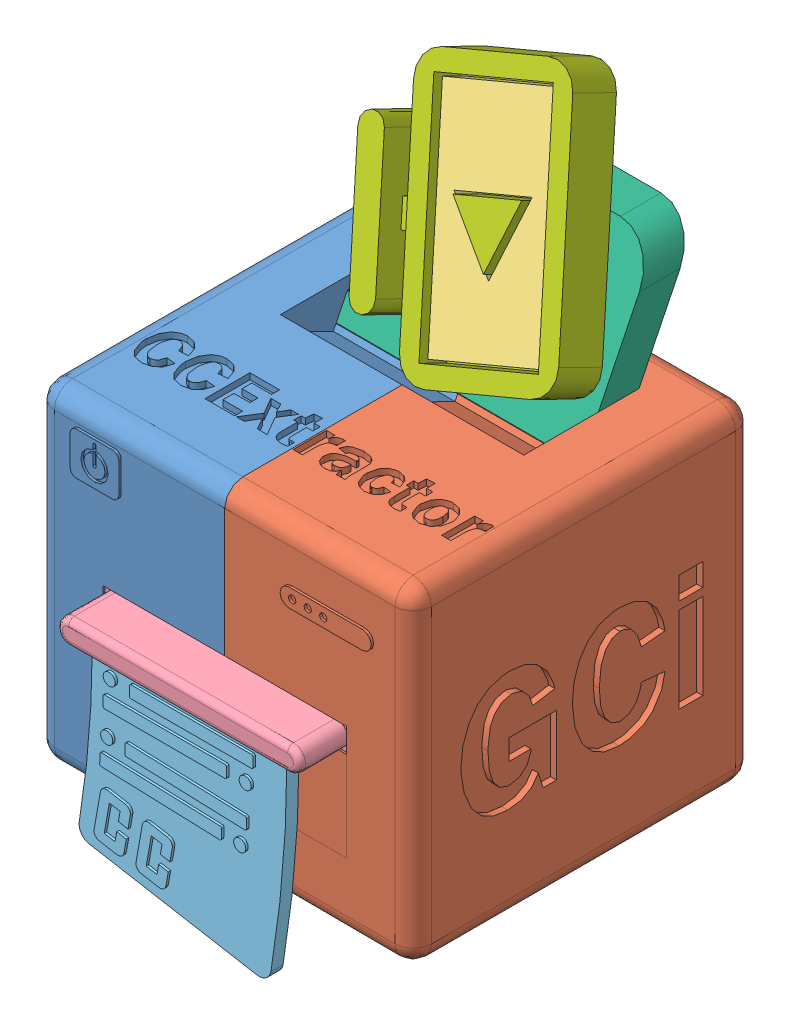
SolidWorks assembly [A] Static-Multi Color Glue, configuration Default. Lengths in mm.
Overall size (590.56 735.11 480.8).
7 component instances, 7 part files, 13 mates.
Components (placement in the parent):
- [P] Static-Multi Color Glue - Main Body Left-2: [P] Static-Multi Color Glue - Main Body Left [Default] at (215.9344 -170.3006 -230.9464) size (196.85 342.9 358.14)
- [P] Static-Multi Color Glue - Main Body Right-2: [P] Static-Multi Color Glue - Main Body Right [Default] at (210.8544 -170.3006 -230.9464) size (245.11 342.9 358.14)
- [P] Static-Multi Color Glue - TV Background-2: [P] Static-Multi Color Glue - TV Background [Default] at (226.7004 271.8639 -165.9811) x (0.34202 -0.843414 0.414337) z (-0.939693 -0.306977 0.150806) size (209.55 25.4 107.95)
- [P] Static-Multi Color Glue - Bill-1: [P] Static-Multi Color Glue - Bill [Default] at (215.9344 -170.3006 -232.9464) size (304.8 88.9 90.8)
- [P] Static-Multi Color Glue - Script-1: [P] Static-Multi Color Glue - Script [Default] at (212.2977 -169.9752 -223.4626) size (217.08 213.82 15.24)
- [P] Static-Multi Color Glue - Tray-1: [P] Static-Multi Color Glue - Tray [Default] at (215.9344 -170.962 -232.2927) size (564.32 506.5 248.82)
- [P] Static-Multi Color Glue - TV-1: [P] Static-Multi Color Glue - TV [Default] at (212.4042 -165.1355 -235.1551) size (249.71 270.56 167.51)
Mates (geometry in assembly coordinates):
- Concentric1: concentric aligned: cylinder of [P] Static-Multi Color Glue - Main Body Left-2 through (162.5944 139.9038 91.9579) axis (1 0 0) radius 25.4; cylinder of [P] Static-Multi Color Glue - Main Body Right-2 through (167.6744 139.9038 91.9579) axis (1 0 0) radius 25.4
- Concentric2: concentric aligned: cylinder of [P] Static-Multi Color Glue - Main Body Left-2 through (162.5944 -137.605 -198.2508) axis (1 0 0) radius 25.4; cylinder of [P] Static-Multi Color Glue - Main Body Right-2 through (167.6744 -137.605 -198.2508) axis (1 0 0) radius 25.4
- Coincident1: coincident anti-aligned: plane of [P] Static-Multi Color Glue - Main Body Left-2 through (27.642 118.1303 -154.1315) normal (0 0.440929 0.897542); plane of [P] Static-Multi Color Glue - Tray-1 through (342.9344 171.938 -180.5652) normal (0 -0.440929 -0.897542)
- Coincident2: coincident anti-aligned: plane of [P] Static-Multi Color Glue - Main Body Left-2 through (-129.7558 122.3632 -145.5151) normal (0 0.897542 -0.440929); plane of [P] Static-Multi Color Glue - Tray-1 through (19.0844 121.7018 -146.8614) normal (0 -0.897542 0.440929)
- Coincident3: coincident anti-aligned: plane of [P] Static-Multi Color Glue - Main Body Left-2 through (88.9344 147.1994 -73.2696) normal (1 0 0); plane of [P] Static-Multi Color Glue - Tray-1 through (88.9344 -170.962 -232.2927) normal (-1 0 0)
- Coincident4: coincident anti-aligned: plane of [P] Static-Multi Color Glue - TV Background-2 through (226.7004 271.8639 -165.9811) normal (0 -0.440929 -0.897542); plane of [P] Static-Multi Color Glue - TV-1 through (212.4042 -52.7991 -6.4864) normal (0 0.440929 0.897542)
- Width1: width anti-aligned: plane of [P] Static-Multi Color Glue - TV Background-2 through (140.1453 354.8631 -178.456) normal (-0.939693 -0.306977 0.150806); plane of [P] Static-Multi Color Glue - TV Background-2 through (313.2555 211.264 -107.9111) normal (0.939693 0.306977 -0.150806); plane of [P] Static-Multi Color Glue - TV-1 through (136.0759 356.5663 -179.2927) normal (0.939693 0.306977 -0.150806); plane of [P] Static-Multi Color Glue - TV-1 through (243.4827 391.6538 -196.5299) normal (-0.939693 -0.306977 0.150806)
- Width2: width anti-aligned: plane of [P] Static-Multi Color Glue - TV-1 through (209.918 174.4732 -89.8372) normal (-0.34202 0.843414 -0.414337); plane of [P] Static-Multi Color Glue - TV-1 through (136.0759 356.5663 -179.2927) normal (0.34202 -0.843414 0.414337); plane of [P] Static-Multi Color Glue - TV Background-2 through (211.8156 178.1257 -91.6316) normal (0.34202 -0.843414 0.414337); plane of [P] Static-Multi Color Glue - TV Background-2 through (241.5851 388.0013 -194.7355) normal (-0.34202 0.843414 -0.414337)
- Coincident5: coincident anti-aligned: plane of [P] Static-Multi Color Glue - Tray-1 through (342.9344 171.938 -138.1159) normal (0 0.440929 0.897542); plane of [P] Static-Multi Color Glue - TV-1 through (119.2935 228.3767 -165.8421) normal (0 -0.440929 -0.897542)
- Coincident6: coincident anti-aligned: plane of [P] Static-Multi Color Glue - Main Body Left-2 through (42.6364 83.6994 82.6536) normal (0 0 1); plane of [P] Static-Multi Color Glue - Bill-1 through (19.0844 37.4446 82.6536) normal (0 0 -1)
- Coincident7: coincident anti-aligned: plane of [P] Static-Multi Color Glue - Main Body Left-2 through (-38.1398 83.6994 84.6536) normal (0 -1 0); plane of [P] Static-Multi Color Glue - Bill-1 through (19.0844 83.6994 107.6536) normal (0 1 0)
- Coincident8: coincident anti-aligned: plane of [P] Static-Multi Color Glue - Main Body Left-2 through (88.9344 147.1994 -73.2696) normal (1 0 0); plane of [P] Static-Multi Color Glue - Bill-1 through (88.9344 46.2464 97.2701) normal (-1 0 0)
- Coincident9: coincident anti-aligned: plane of [P] Static-Multi Color Glue - Main Body Left-2 through (215.9344 -170.3006 -230.9464) normal (1 0 0); plane of [P] Static-Multi Color Glue - Main Body Right-2 through (215.9344 -170.3006 -230.9464) normal (-1 0 0)
